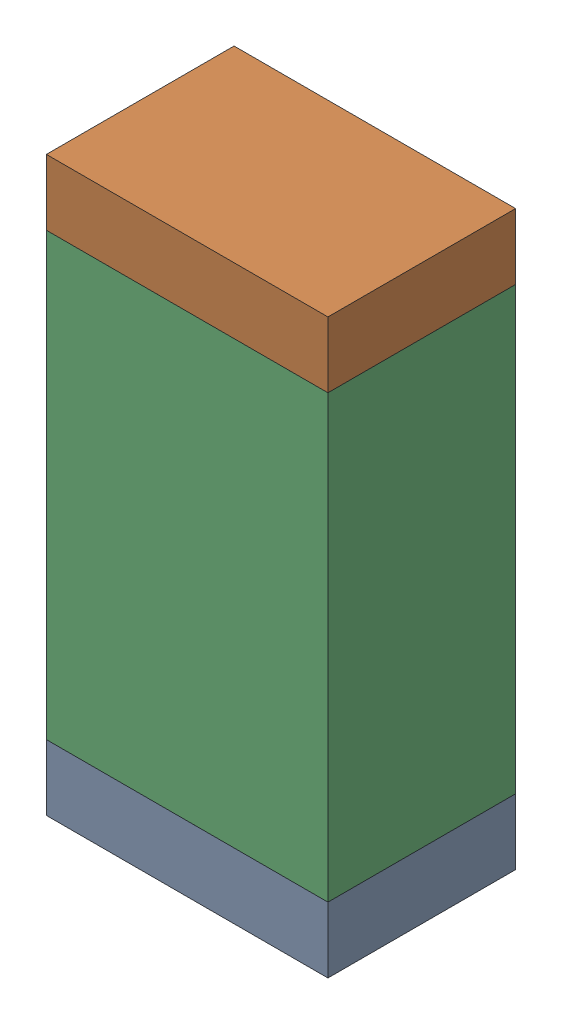
SolidWorks assembly R5, configuration Default. Lengths in mm.
Overall size (0.76 1.55 0.51).
6 component instances, 2 part files, 0 mates.
Components (placement in the parent):
- 822501776-1: 822501776 [Default] at (29.0325 16.7307 0) size (0.76 0.18 0.51)
  - Extruded_3-1: Extruded_3 [Default] at origin size (0.76 0.18 0.51)
- 822501776-2: 822501776 [Default] at (29.0325 18.1023 0) size (0.76 0.18 0.51)
  - Extruded_3-1: Extruded_3 [Default] at origin size (0.76 0.18 0.51)
- 822501912-1: 822501912 [Default] at (29.0325 17.4165 0) size (0.76 1.19 0.51)
  - Extruded_4-1: Extruded_4 [Default] at origin size (0.76 1.19 0.51)
